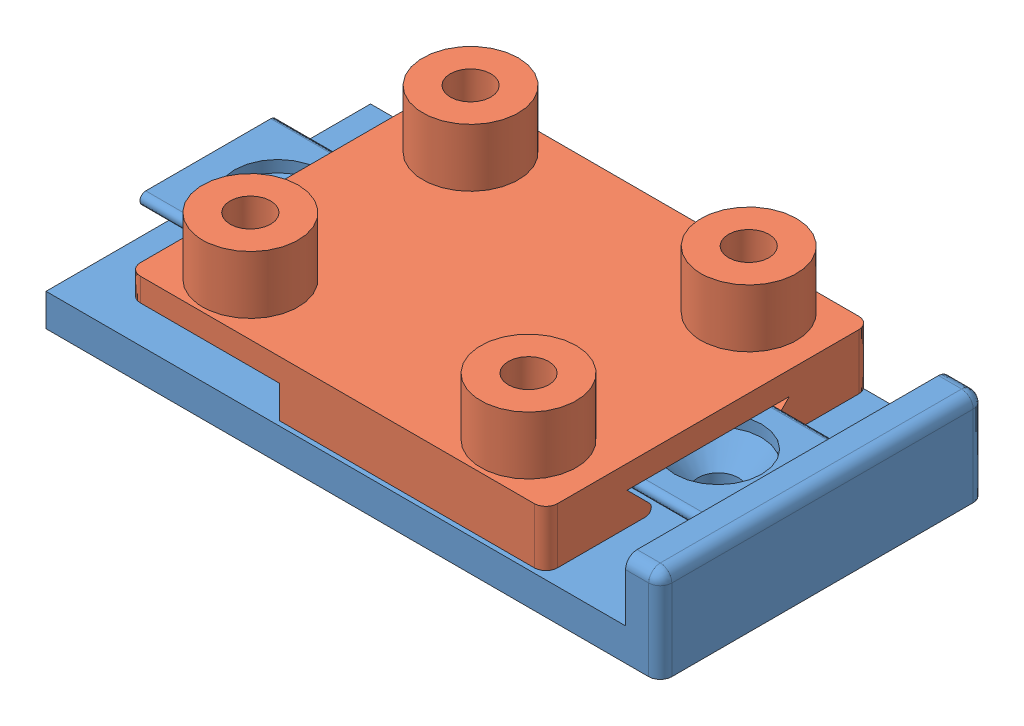
SolidWorks assembly assemblage_support_photodiode, configuration Défaut. Lengths in mm.
Overall size (53 13 28).
2 component instances, 2 part files, 2 mates.
Components (placement in the parent):
- support_photodiode_b-1: support_photodiode_b [Défaut] at (-30.3789 -18.1026 36) size (53 8 28)
- support_photodiode_h-1: support_photodiode_h [Défaut] at (-27.979 -14.9026 60.2137) x (0 0 1) z (0 1 0) size (28 36 9.8)
Mates (geometry in assembly coordinates):
- Coïncidente2: coincident aligned: plane of support_photodiode_b-1 through (-30.3789 -12.1026 36) normal (0 0 -1); plane of support_photodiode_h-1 through (12.754 -10.1026 36) normal (0 0 -1)
- Coïncidente3: coincident anti-aligned: plane of support_photodiode_b-1 through (-30.3789 -12.1026 36) normal (0 1 0); plane of support_photodiode_h-1 through (12.754 -12.1026 43) normal (0 -1 0)
